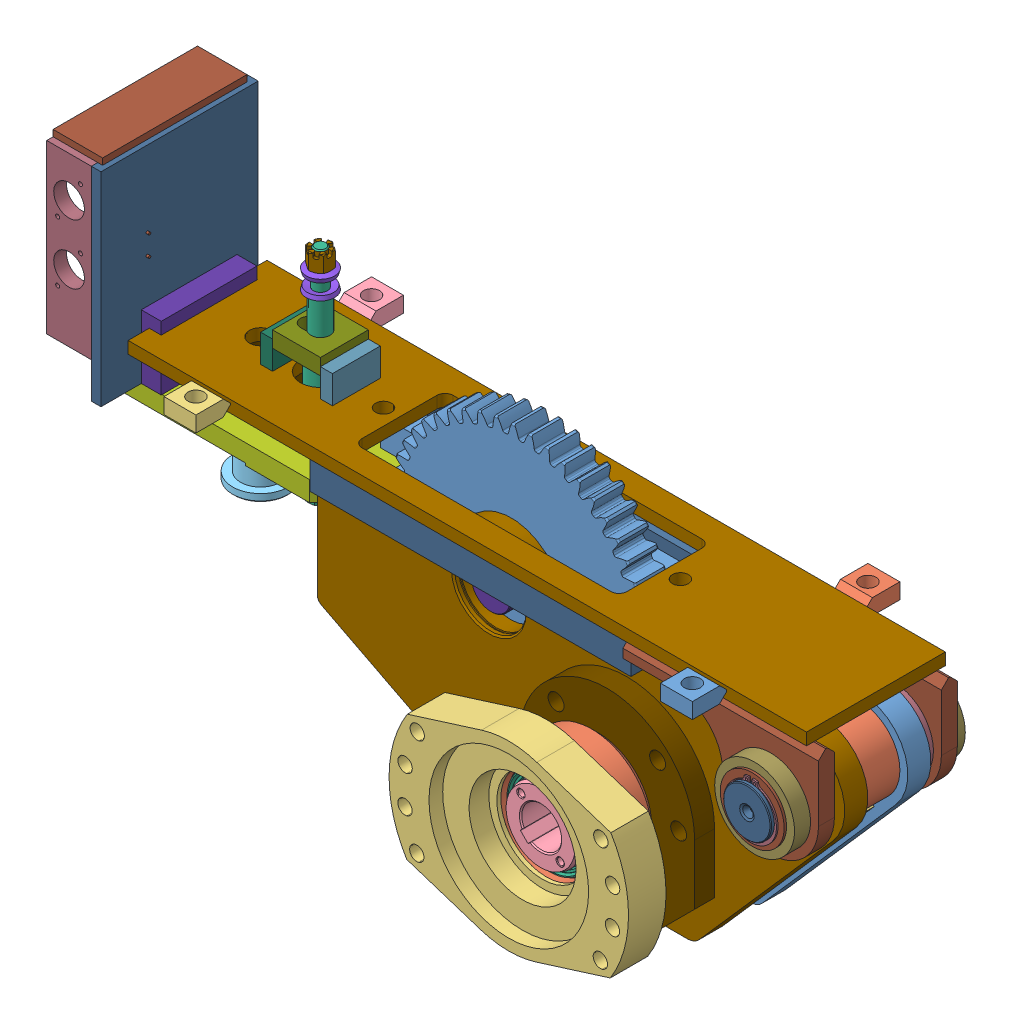
SolidWorks assembly g1_3_1_1, configuration 默认. Lengths in mm.
Overall size (943 530 331.8).
107 component instances, 72 part files, 35 mates.
Components (placement in the parent):
- g1_3_1_1_5_1-1: g1_3_1_1_5_1 [默认] at (1636.5961 -95 30) x (-1 0 0) z (0 1 0) size (926 108 318.6)
  - g1_3_1_1_5-1_af1_1-1: g1_3_1_1_5-1_af1_1 [默认] at origin size (661 29 318.6)
  - g1_3_1_1_5-2_af0_1-1: g1_3_1_1_5-2_af0_1 [默认] at (-213.2 29 0) size (100 50 100)
  - g1_3_1_1_5-4_1-1: g1_3_1_1_5-4_1 [默认] at (-149.9151 54 -132.7301) x (0 1 0) z (-0.659692 0 0.751536) size (50 10 223)
  - g1_3_1_1_5-5_1-1: g1_3_1_1_5-5_1 [默认] at (20.5 54 -217) x (1 0 0) z (0 1 0) size (194 10 50)
  - g1_3_1_1_5-6_1-1: g1_3_1_1_5-6_1 [默认] at (248.4498 54 -161.5242) x (0 1 0) z (0.890083 0 0.455798) size (50 10 284)
  - g1_3_1_1_5-7_1-1: g1_3_1_1_5-7_1 [默认] at (377.8 54 -43.9) x (0 0 -1) z (0 1 0) size (87 10 50)
  - g1_3_1_1_5-9_af0_1-1: g1_3_1_1_5-9_af0_1 [默认] at (502.8 54 24.6) x (1 0 0) z (0 1 0) size (300 25 108)
  - g1_3_1_1_5-8_1-1: g1_3_1_1_5-8_1 [默认] at (437.8 54 49.6) x (1 0 0) z (0 1 0) size (60 50 60)
  - g1_3_1_1_5-1_af0_1-1: g1_3_1_1_5-1_af0_1 [默认] at (0 79 0) size (661 29 318.6)
- g1_3_1_1_4_1-1: g1_3_1_1_4_1 [默认] at (1849.7961 -95 -33.3) x (1 0 0) z (0 -1 0) size (80 234 80)
  - g1_3_1_1_4-1_1-1: g1_3_1_1_4-1_1 [默认] at origin size (60 234 60.04)
  - g1_3_1_1_4-3_1-2: g1_3_1_1_4-3_1 [默认] at (0 224.3 0) size (80 3 80)
  - g1_3_1_1_4-2_1-1: g1_3_1_1_4-2_1 [默认] at (0 174.3 0) size (72 50 72)
  - g1_3_1_1_4-2_1-2: g1_3_1_1_4-2_1 [默认] at (0 9.7 0) size (72 50 72)
  - g1_3_1_1_4-2_1-3: g1_3_1_1_4-2_1 [默认] at (0 62.7 0) size (72 50 72)
  - g1_3_1_1_4-2_1-4: g1_3_1_1_4-2_1 [默认] at (0 121.3 0) size (72 50 72)
  - 60_gb894_1_1-2: 60_gb894_1_1 [默认] at (1.95 227.5 -28.4332) x (-1 0 0) z (0 1 0) size (65.16 69.76 2)
- g1_3_1_1_2_1-1: g1_3_1_1_2_1 [默认] at (1636.5961 -195.4 0) x (0.99999 -0.004549 0) z (-0.004549 -0.99999 0) size (219.6 152 245)
  - g1_3_1_1_2-1_1-1: g1_3_1_1_2-1_1 [默认] at origin size (219.6 61 245)
  - g1_3_1_1_2-2_1-1: g1_3_1_1_2-2_1 [默认] at (0 152 0) x (-0.047609 0 0.998866) z (0 1 0) size (120.16 120.16 117)
  - g1_3_1_1_2-3_1-1: g1_3_1_1_2-3_1 [默认] at (-20.1525 129 20.1525) x (0 -1 0) z (0.707107 0 0.707107) size (28 11 14)
- g1_3_1_1_3_1-1: g1_3_1_1_3_1 [默认] at (1463.7961 -78.4 83.75) x (0 0 -1) z (0 -1 0) size (103.5 321.87 322.01)
  - g1_3_1_1_3-1_1-1: g1_3_1_1_3-1_1 [默认] at origin size (103.5 52 52)
  - 16x10x45_gb1096_1-1: 16x10x45_gb1096_1 [默认] at (-0.5 0 25) x (1 0 0) z (0 0 -1) size (45 16 10)
  - _X2_60F08F6E_X0_g1_3_1_1_3-2_1-1: _X2_60F08F6E_X0_g1_3_1_1_3-2_1 [默认] at (25 0 0) x (0 0 1) z (1 0 0) size (322.01 321.87 50.08)
- g1_3_1_1_1_2-1: g1_3_1_1_1_2 [默认] at (1636.5961 -195.4 123.8) x (0.99999 -0.004549 0) z (-0.004549 -0.99999 0) size (300 165.8 228)
  - g1_3_1_1_1_1_1-1: g1_3_1_1_1_1_1 [默认] at origin size (300 112 228)
    - g1_3_1_1_1_1-2_af0_1-1: g1_3_1_1_1_1-2_af0_1 [默认] at (0 50 0) size (150 65 150)
    - g1_3_1_1_1_1-3_af0_1-1: g1_3_1_1_1_1-3_af0_1 [默认] at (0 140 0) size (300 47 228)
  - g1_3_1_1_1-2_1-1: g1_3_1_1_1-2_1 [默认] at (0 122.2 0) x (0.707107 0 0.707107) z (0.707107 0 -0.707107) size (90 126 90)
  - g1_3_1_1_1-1_1-1: g1_3_1_1_1-1_1 [默认] at (0 77 0) x (0 1 0) z (0 0 1) size (20 110 110)
  - b90x110x12_gb9877_1_1-1: b90x110x12_gb9877_1_1 [默认] at (0 66.9 0) size (108.6 17.9 108.6)
    - b90x110x12_gb9877_1_rubber_1-1: b90x110x12_gb9877_1_rubber_1 [默认] at origin size (108.6 12 108.6)
    - b90x110x12_gb9877_1_frame_1-1: b90x110x12_gb9877_1_frame_1 [默认] at (0 -2.4 0) x (-1 0 0) z (0 0 1) size (107.2 9.5 107.2)
  - b90x110x12_gb9877_1_1-2: b90x110x12_gb9877_1_1 [默认] at (0 104.8 0) size (108.6 17.9 108.6)
    - b90x110x12_gb9877_1_rubber_1-1: b90x110x12_gb9877_1_rubber_1 [默认] at origin size (108.6 12 108.6)
    - b90x110x12_gb9877_1_frame_1-1: b90x110x12_gb9877_1_frame_1 [默认] at (0 -2.4 0) x (-1 0 0) z (0 0 1) size (107.2 9.5 107.2)
  - 80_gb894_1_1-1: 80_gb894_1_1 [默认] at (-2.4 11.1 -38.1746) x (1 0 0) z (0 -1 0) size (85.83 90.87 2.5)
- g1_3_1_1_6_1-1: g1_3_1_1_6_1 [默认] at (1463.7961 0 84) x (-1 0 0) z (0 0 1) size (875 200 260)
  - g1_3_1_1_6-4_af0_1-1: g1_3_1_1_6-4_af0_1 [默认] at origin size (850 15 174)
  - g1_3_1_1_6-8_1-1: g1_3_1_1_6-8_1 [默认] at (0 40 57) x (1 0 0) z (0 -1 0) size (402 20 44.8)
  - g1_3_1_1_6-8_1-2: g1_3_1_1_6-8_1 [默认] at (0 40 -77) x (1 0 0) z (0 -1 0) size (402 20 44.8)
  - g1_3_1_1_6-1_1-1: g1_3_1_1_6-1_1 [默认] at (-386 95 -87) x (1 0 0) z (0 -1 0) size (245 20 140)
  - g1_3_1_1_6-1_1-2: g1_3_1_1_6-1_1 [默认] at (-386 95 67) x (1 0 0) z (0 -1 0) size (245 20 140)
  - g1_3_1_1_6-3_1-1: g1_3_1_1_6-3_1 [默认] at (-386 95 87) x (-1 0 0) z (0 1 0) size (100 20 100)
  - g1_3_1_1_6-3_1-2: g1_3_1_1_6-3_1 [默认] at (-386 95 -107) x (-1 0 0) z (0 1 0) size (100 20 100)
  - g1_3_1_1_6-2_1-1: g1_3_1_1_6-2_1 [默认] at (-386 95 57) x (-1 0 0) z (0 1 0) size (100 10 100)
  - g1_3_1_1_6-2_1-2: g1_3_1_1_6-2_1 [默认] at (-386 95 -57) x (1 0 0) z (0 1 0) size (100 10 100)
  - g1_3_1_1_6-9_1-1: g1_3_1_1_6-9_1 [默认] at (220 -17 0) x (0 1 0) z (0 0 -1) size (35 15 60)
  - g1_3_1_1_6-9_af0_1-1: g1_3_1_1_6-9_af0_1 [默认] at (310 -17 0) x (0 1 0) z (0 0 1) size (35 15 60)
  - g1_3_1_1_6-10_1-1: g1_3_1_1_6-10_1 [默认] at (265 -45 0) size (60 20 60)
  - g1_3_1_1_6-12_af0_1-1: g1_3_1_1_6-12_af0_1 [默认] at (434 25 0.5) x (0 0 1) z (0 -1 0) size (120 25 80)
  - g1_3_1_1_6-11_af0_1-1: g1_3_1_1_6-11_af0_1 [默认] at (357 15 0) size (94 40 60)
  - g1_3_1_1_6-5_af0_1-1: g1_3_1_1_6-5_af0_1 [默认] at (-311 -5 108.5) x (0 0 -1) z (1 0 0) size (43 19.6 40)
  - g1_3_1_1_6-5_af1_1-1: g1_3_1_1_6-5_af1_1 [默认] at (-311 -5 -108.5) x (0 0 1) z (-1 0 0) size (43 19.6 40)
  - g1_3_1_1_6-5_af2_1-1: g1_3_1_1_6-5_af2_1 [默认] at (311 -5 108.5) x (0 0 -1) z (1 0 0) size (43 19.6 40)
  - g1_3_1_1_6-5_af3_1-1: g1_3_1_1_6-5_af3_1 [默认] at (311 -5 -108.5) x (0 0 1) z (-1 0 0) size (43 19.6 40)
- g1_3_1_1-1_1-1: g1_3_1_1-1_1 [默认] at (1123.7961 -45.5 84) x (0.999708 0 0.02418) z (0.02418 0 -0.999708) size (70 135 70)
- g1_3_1_1_7_1-1: g1_3_1_1_7_1 [默认] at (1198.7961 49.5833 84) x (0 1 0) z (0.554222 0 -0.832369) size (272.02 63.51 60)
  - g1_3_1_1_7-1_1-1: g1_3_1_1_7-1_1 [默认] at origin size (272.02 60 60)
  - g1_3_1_1_7-2_1-1: g1_3_1_1_7-2_1 [默认] at (-104.3833 -31.7543 0) x (0 1 0) z (1 0 0) size (63.51 55 25)
  - a35_5_gb1972_1-1: a35_5_gb1972_1 [默认] at (39.2167 0 0) x (0 0.075145 0.997173) z (0 0.997173 -0.075145) size (35.5 7.2 35.5)
  - a35_5_gb1972_1-2: a35_5_gb1972_1 [默认] at (62.8167 0 0) x (0 -0.99777 0.066751) z (0 -0.066751 -0.99777) size (35.5 7.2 35.5)
  - m16a_gb6178_1-1: m16a_gb6178_1 [默认] at (85.8167 13.8564 0) x (0 -1 0) z (-1 0 0) size (27.71 24 20.8)
- g1_3_1_1_8_1-1: g1_3_1_1_8_1 [默认] at (1034.7961 62.5 96.5) x (0 0 -1) z (0 1 0) size (197 71 268.3)
  - g1_3_1_1_8_1_af0_1-1: g1_3_1_1_8_1_af0_1 [默认] at origin size (197 68 263)
    - g1_3_1_1_8_1-3_af1_1-1: g1_3_1_1_8_1-3_af1_1 [默认] at origin size (197 12 255)
    - g1_3_1_1_8_1-1_1-1: g1_3_1_1_8_1-1_1 [默认] at (0 37 127.5) x (1 0 0) z (0 -1 0) size (181 8 62)
    - g1_3_1_1_8_1-2_af1_1-1: g1_3_1_1_8_1-2_af1_1 [默认] at (98.5 40 22.5) x (0 1 0) z (0 0 1) size (56 16 210)
    - g1_3_1_1_8_1-2_af0_1-1: g1_3_1_1_8_1-2_af0_1 [默认] at (-98.5 40 22.5) x (0 1 0) z (0 0 -1) size (56 16 210)
    - g1_3_1_1_8_1-5_1-1: g1_3_1_1_8_1-5_1 [默认] at (0 40 -82.5) x (1 0 0) z (0 1 0) size (165 8 56)
    - g1_3_1_1_8_1-6_1-1: g1_3_1_1_8_1-6_1 [默认] at (27.5 40 -106) x (0 1 0) z (0 0 -1) size (56 6 31)
    - g1_3_1_1_8_1-6_1-2: g1_3_1_1_8_1-6_1 [默认] at (-8.5 40 -106) x (0 1 0) z (0 0 -1) size (56 6 31)
    - g1_3_1_1_8_1-4_af1_1-1: g1_3_1_1_8_1-4_af1_1 [默认] at (-10 12 5) size (105 17 85)
    - g1_3_1_1_8_1-8_af0_1-1: g1_3_1_1_8_1-8_af0_1 [默认] at (12.5 40 -127.5) x (0 1 0) z (1 0 0) size (56 6 54)
  - g1_3_1_1_8-3_1-1: g1_3_1_1_8-3_1 [默认] at (12.5 37 -32.7987) x (0 0 -1) z (0 1 0) size (229 15 15)
  - g1_3_1_1_8-6_1-1: g1_3_1_1_8-6_1 [默认] at (12.5 37 30.1) x (-1 0 0) z (0 1 0) size (26 60 26)
  - g1_3_1_1_8-5_1-1: g1_3_1_1_8-5_1 [默认] at (12.5 29 -27.5) size (60 24 20)
  - g1_3_1_1_8-9_af0_1-1: g1_3_1_1_8-9_af0_1 [默认] at (-42.5 17 5.5) size (34 10 74)
  - g1_3_1_1_8-10_1-1: g1_3_1_1_8-10_1 [默认] at (12.5 37 -127.5) x (1 0 0) z (0 1 0) size (40 2 32)
  - ya2x20x90-2_gb2089_af0_1-1: ya2x20x90-2_gb2089_af0_1 [默认] at (12.5 37 -82.5) x (0 0 -1) z (1 0 0) size (92.3 24.62 24.71)
  - 14x2_65_gb3452_1_1-1: 14x2_65_gb3452_1_1 [默认] at (12.5 37 -124.5) x (0 0 1) z (0 1 0) size (2.65 19.37 19.38)
  - 15_gb894_1_1-1: 15_gb894_1_1 [默认] at (12 29.8675 -73.9) size (17.18 18.67 1.11)
  - 15_gb894_1_1-2: 15_gb894_1_1 [默认] at (12 29.8675 29) size (17.18 18.67 1.11)
  - 8_gb93_1-1: 8_gb93_1 [默认] at (32.5 53 -27.5) x (-1 0 0) z (0 1 0) size (12.3 12.3 2.1)
  - m8x40_gb5782_1-1: m8x40_gb5782_1 [默认] at (32.5 55.1 -27.5) size (15.01 45.3 13)
  - 8_gb93_1-2: 8_gb93_1 [默认] at (-7.5 53 -27.5) x (-1 0 0) z (0 1 0) size (12.3 12.3 2.1)
  - m8x40_gb5782_1-2: m8x40_gb5782_1 [默认] at (-7.5 55.1 -27.5) size (15.01 45.3 13)
  - m3x10_gb818_1-1: m3x10_gb818_1 [默认] at (57.5 2 60.5) size (5.81 12.5 5.77)
  - m3x10_gb818_1-2: m3x10_gb818_1 [默认] at (57.5 2 100.5) size (5.81 12.5 5.77)
  - m3x10_gb818_1-3: m3x10_gb818_1 [默认] at (-17.5 2 100.5) size (5.81 12.5 5.77)
  - m3x10_gb818_1-4: m3x10_gb818_1 [默认] at (-57.5 2 100.5) size (5.81 12.5 5.77)
  - m3x30_gb818_1-1: m3x30_gb818_1 [默认] at (-40.5 -3 7.5) size (5.81 32.5 5.77)
  - m3x30_gb818_1-2: m3x30_gb818_1 [默认] at (-40.5 -3 32.9) size (5.81 32.5 5.77)
  - 6_gb93_1-9: 6_gb93_1 [默认] at (-52.5 28.6 -17.5) x (1 0 0) z (0 -1 0) size (9.3 9.3 1.6)
  - m6x20_gb5783_1-9: m6x20_gb5783_1 [默认] at (-52.5 28.6 -17.5) size (11.55 24 10)
  - 6_gb93_1-10: 6_gb93_1 [默认] at (-32.5 28.6 -17.5) x (1 0 0) z (0 -1 0) size (9.3 9.3 1.6)
  - m6x20_gb5783_1-10: m6x20_gb5783_1 [默认] at (-32.5 28.6 -17.5) size (11.55 24 10)
  - 5x14_gb119_2_1-1: 5x14_gb119_2_1 [默认] at (-42.5 27 -3.5) size (5 14 5)
  - m3x6_gb818_1-1: m3x6_gb818_1 [默认] at (27.5 37 -123.5) x (1 0 0) z (0 1 0) size (5.81 8.5 5.77)
  - m3x6_gb818_1-2: m3x6_gb818_1 [默认] at (-2.5 37 -123.5) x (1 0 0) z (0 1 0) size (5.81 8.5 5.77)
- _X2_57AB5708_X0_16_gb93_1-9: _X2_57AB5708_X0_16_gb93_1 [默认] at (1022.7961 -50 44) x (0 0.924225 0.381849) z (-1 0 0) size (24.4 24.4 4.1)
- _X2_87BA6813_X0_m16x35_gb5783_10_1-1: _X2_87BA6813_X0_m16x35_gb5783_10_1 [默认] at (1018.6961 -50 44) x (0 -0.866025 -0.5) z (0 0.5 -0.866025) size (27.71 45 24)
- _X2_57AB5708_X0_16_gb93_1-10: _X2_57AB5708_X0_16_gb93_1 [默认] at (1022.7961 -50 124) x (0 0.924225 0.381849) z (-1 0 0) size (24.4 24.4 4.1)
- _X2_87BA6813_X0_m16x35_gb5783_10_1-2: _X2_87BA6813_X0_m16x35_gb5783_10_1 [默认] at (1018.6961 -50 124) x (0 -0.866025 -0.5) z (0 0.5 -0.866025) size (27.71 45 24)
- g1_3_1_1_1_1-1_af0_1-1: g1_3_1_1_1_1-1_af0_1 [默认] at (1636.5961 -195.4 113) x (1 0 0) z (0 -1 0) size (220 42 245)
Mates (geometry in assembly coordinates):
- 重合1: coincident anti-aligned: plane of g1_3_1_1_2_1-1/g1_3_1_1_2-3_1-1 through (1611.4249 -210.4885 129) normal (-0.703883 0.710316 0); plane of g1_3_1_1_1_2-1/g1_3_1_1_1-2_1-1 through (1611.2118 -210.6996 246) normal (0.703883 -0.710316 0)
- 重合2: coincident anti-aligned: plane of g1_3_1_1_2_1-1/g1_3_1_1_2-2_1-1 through (1636.5961 -195.4 120) normal (0 0 1); plane of g1_3_1_1_1_2-1/g1_3_1_1_1-2_1-1 through (1636.5961 -195.4 120) normal (0 0 -1)
- 同心3: concentric aligned: cylinder of g1_3_1_1_2_1-1/g1_3_1_1_2-2_1-1 through (1636.5961 -195.4 29.15) axis (0 0 1) radius 25; cylinder of g1_3_1_1_1_2-1/g1_3_1_1_1-2_1-1 through (1636.5961 -195.4 246) axis (0 0 1) radius 25
- 同心9: concentric anti-aligned: cylinder of g1_3_1_1_8_1-1/g1_3_1_1_8_1_af0_1-1/g1_3_1_1_8_1-3_af1_1-1 through (1022.7961 -50 124) axis (1 0 0) radius 8.5; cylinder of _X2_87BA6813_X0_m16x35_gb5783_10_1-2 through (1055.4461 -50 124) axis (-1 0 0) radius 8
- 同心12: concentric anti-aligned: cylinder of g1_3_1_1_6_1-1/g1_3_1_1_6-12_af0_1-1 through (1078.3124 -50 44) axis (1 0 0) radius 7; cylinder of _X2_87BA6813_X0_m16x35_gb5783_10_1-1 through (1055.4461 -50 44) axis (-1 0 0) radius 8
- 同心13: concentric aligned: cylinder of _X2_57AB5708_X0_16_gb93_1-10 through (1022.7961 -50 124) axis (-1 0 0) radius 8.1; cylinder of _X2_87BA6813_X0_m16x35_gb5783_10_1-2 through (1055.4461 -50 124) axis (-1 0 0) radius 8
- 同心14: concentric aligned: cylinder of _X2_57AB5708_X0_16_gb93_1-9 through (1022.7961 -50 44) axis (-1 0 0) radius 8.1; cylinder of _X2_87BA6813_X0_m16x35_gb5783_10_1-1 through (1055.4461 -50 44) axis (-1 0 0) radius 8
- 重合3: coincident anti-aligned: plane of _X2_57AB5708_X0_16_gb93_1-9 through (1018.6961 -50 44) normal (-1 0 0); plane of _X2_87BA6813_X0_m16x35_gb5783_10_1-1 through (1018.6961 -50 44) normal (1 0 0)
- 重合4: coincident anti-aligned: plane of _X2_57AB5708_X0_16_gb93_1-10 through (1018.6961 -50 124) normal (-1 0 0); plane of _X2_87BA6813_X0_m16x35_gb5783_10_1-2 through (1018.6961 -50 124) normal (1 0 0)
- 同心15: concentric aligned: cylinder of g1_3_1_1_8_1-1/g1_3_1_1_8_1_af0_1-1/g1_3_1_1_8_1-3_af1_1-1 through (1022.7961 -50 44) axis (-1 0 0) radius 8.5; cylinder of _X2_87BA6813_X0_m16x35_gb5783_10_1-1 through (1055.4461 -50 44) axis (-1 0 0) radius 8
- 同心18: concentric aligned: cylinder of g1_3_1_1_6_1-1/g1_3_1_1_6-11_af0_1-1 through (1123.7961 71.0063 84) axis (0 -1 0) radius 14; cylinder of g1_3_1_1-1_1-1 through (1123.7961 -19.25 84) axis (0 -1 0) radius 15
- 同心20: concentric anti-aligned: cylinder of g1_3_1_1_5_1-1/g1_3_1_1_5-9_af0_1-1 through (1123.7961 -95.4 84) axis (0 1 0) radius 27; cylinder of g1_3_1_1-1_1-1 through (1123.7961 -50.5 84) axis (0 -1 0) radius 25
- 重合10: coincident anti-aligned: plane of g1_3_1_1_8_1-1/g1_3_1_1_8_1_af0_1-1/g1_3_1_1_8_1-3_af1_1-1 through (1022.7961 62.5 96.5) normal (-1 0 0); plane of _X2_57AB5708_X0_16_gb93_1-9 through (1022.7961 -50 44) normal (1 0 0)
- 重合12: coincident anti-aligned: plane of g1_3_1_1_8_1-1/g1_3_1_1_8_1_af0_1-1/g1_3_1_1_8_1-3_af1_1-1 through (1022.7961 62.5 96.5) normal (-1 0 0); plane of _X2_57AB5708_X0_16_gb93_1-10 through (1022.7961 -50 124) normal (1 0 0)
- 同心21: concentric aligned: cylinder of g1_3_1_1_5_1-1/g1_3_1_1_5-8_1-1 through (1198.7961 -103.15 84) axis (0 1 0) radius 14.75; cylinder of g1_3_1_1_7_1-1/g1_3_1_1_7-1_1-1 through (1198.7961 -405.7188 84) axis (0 1 0) radius 16
- 重合13: coincident anti-aligned: plane of g1_3_1_1_6_1-1/g1_3_1_1_6-12_af0_1-1 through (1034.7961 0 84) normal (-1 0 0); plane of g1_3_1_1_8_1-1/g1_3_1_1_8_1_af0_1-1/g1_3_1_1_8_1-3_af1_1-1 through (1034.7961 62.5 96.5) normal (1 0 0)
- 同心23: concentric aligned: cylinder of g1_3_1_1_5_1-1/g1_3_1_1_5-1_af1_1-1 through (1849.7961 -95 30) axis (0 0 1) radius 36; cylinder of g1_3_1_1_6_1-1/g1_3_1_1_6-3_1-2 through (1849.7961 -95 -23) axis (0 0 1) radius 36
- 同心24: concentric aligned: cylinder of g1_3_1_1_4_1-1/g1_3_1_1_4-2_1-2 through (1849.7961 -95 -23.6) axis (0 0 1) radius 36; cylinder of g1_3_1_1_6_1-1/g1_3_1_1_6-3_1-2 through (1849.7961 -95 -23) axis (0 0 1) radius 36
- 重合14: coincident anti-aligned: plane of g1_3_1_1_4_1-1/g1_3_1_1_4-3_1-2 through (1849.7961 -95 191) normal (0 0 -1); plane of g1_3_1_1_6_1-1/g1_3_1_1_6-3_1-1 through (1849.7961 -95 191) normal (0 0 1)
- 重合15: coincident anti-aligned: plane of g1_3_1_1_5_1-1/g1_3_1_1_5-8_1-1 through (1198.7961 -95.4 84) normal (0 -1 0); plane of g1_3_1_1_7_1-1/g1_3_1_1_7-1_1-1 through (1198.7961 -95.4 84) normal (0 1 0)
- 同心25: concentric aligned: cylinder of g1_3_1_1_5_1-1/g1_3_1_1_5-1_af1_1-1 through (1463.7961 -78.4 30) axis (0 0 1) radius 45; cylinder of g1_3_1_1_3_1-1/g1_3_1_1_3-1_1-1 through (1463.7961 -78.4 26.825) axis (0 0 1) radius 25
- 同心26: concentric aligned: cylinder of g1_3_1_1_5_1-1/g1_3_1_1_5-1_af1_1-1 through (1636.5961 -195.4 30) axis (0 0 1) radius 75; cylinder of g1_3_1_1_2_1-1/g1_3_1_1_2-1_1-1 through (1636.5961 -195.4 30) axis (0 0 1) radius 75
- 重合16: coincident anti-aligned: plane of g1_3_1_1_5_1-1/g1_3_1_1_5-1_af1_1-1 through (1636.5961 -95 30) normal (0 0 -1); plane of g1_3_1_1_2_1-1/g1_3_1_1_2-1_1-1 through (1636.5961 -195.4 30) normal (0 0 1)
- 重合17: coincident anti-aligned: plane of g1_3_1_1_5_1-1/g1_3_1_1_5-1_af1_1-1; plane of ? through (523.5275 -270.9624 278.2595) normal (0 -1 0)
- 重合19: coincident aligned: plane of g1_3_1_1_5_1-1/g1_3_1_1_5-1_af0_1-1 through (1463.7961 -78.4 128.8) normal (0 0 1); plane of g1_3_1_1_3_1-1/g1_3_1_1_3-1_1-1 through (1463.7961 -78.4 128.8) normal (0 0 1)
- 重合28: coincident anti-aligned: plane of g1_3_1_1_2_1-1/g1_3_1_1_2-1_1-1 through (1636.5961 -195.4 0) normal (0 0 -1); plane of assembly through (0 0 0) normal (0 0 1)
- 重合31: coincident aligned: plane of g1_3_1_1_6_1-1/g1_3_1_1_6-4_af0_1-1 through (1463.7961 0 84) normal (0 1 0); plane of assembly through (0 0 0) normal (0 1 0)
- 同心28: concentric aligned: cylinder of g1_3_1_1_6_1-1/g1_3_1_1_6-12_af0_1-1 through (1078.3124 -50 124) axis (-1 0 0) radius 7; cylinder of _X2_87BA6813_X0_m16x35_gb5783_10_1-2 through (1055.4461 -50 124) axis (-1 0 0) radius 8
- 同心29: concentric aligned: cylinder of g1_3_1_1_5_1-1/g1_3_1_1_5-1_af0_1-1 through (1636.5961 -195.4 109) axis (0 0 1) radius 75; cylinder of g1_3_1_1_1_1-1_af0_1-1 through (1636.5961 -195.4 -384.4109) axis (0 0 1) radius 75
- 同心30: concentric aligned: cylinder of g1_3_1_1_5_1-1/g1_3_1_1_5-1_af0_1-1 through (1572.9961 -131.8 108.5324) axis (0 0 1) radius 5.1; cylinder of g1_3_1_1_1_1-1_af0_1-1 through (1572.9961 -131.8 163) axis (0 0 1) radius 10
- 重合33: coincident anti-aligned: plane of g1_3_1_1_5_1-1/g1_3_1_1_5-1_af0_1-1 through (1636.5961 -95 138) normal (0 0 1); plane of g1_3_1_1_1_1-1_af0_1-1 through (1636.5961 -195.4 138) normal (0 0 -1)
- 平行2: parallel aligned: plane of g1_3_1_1_4_1-1/60_gb894_1_1-2 through (1847.8461 -66.5668 194.2) normal (1 0 0); plane of g1_3_1_1_6_1-1/g1_3_1_1_6-1_1-2 through (1909.7961 -95 151) normal (1 0 0)
- 重合37: coincident anti-aligned: plane of g1_3_1_1_6_1-1/g1_3_1_1_6-11_af0_1-1 through (1153.7961 -50.5 114) normal (0 -1 0); plane of g1_3_1_1-1_1-1 through (1123.7961 -50.5 84) normal (0 1 0)
- 平行5: parallel anti-aligned: plane of g1_3_1_1_8_1-1/g1_3_1_1_8_1_af0_1-1/g1_3_1_1_8_1-5_1-1 through (994.7961 -28 96.5) normal (0 -1 0); plane of _X2_87BA6813_X0_m16x35_gb5783_10_1-2 through (1018.6961 -38 130.9282) normal (0 1 0)
- 平行6: parallel anti-aligned: plane of g1_3_1_1_8_1-1/g1_3_1_1_8_1_af0_1-1/g1_3_1_1_8_1-5_1-1 through (994.7961 -28 96.5) normal (0 -1 0); plane of _X2_87BA6813_X0_m16x35_gb5783_10_1-1 through (1018.6961 -38 50.9282) normal (0 1 0)
